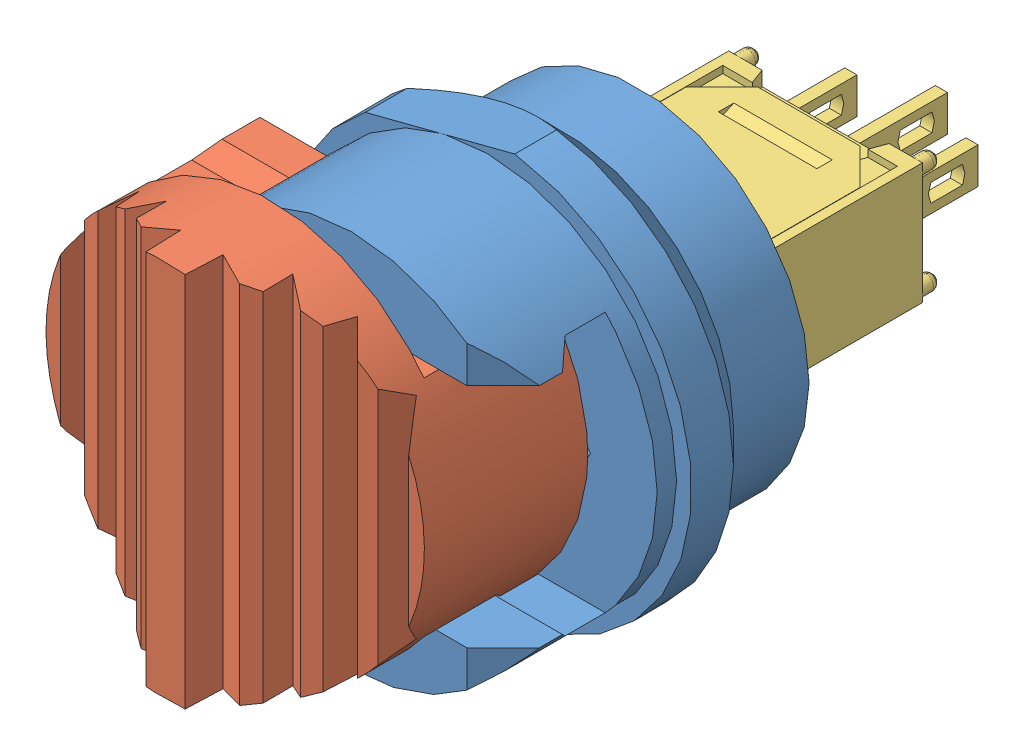
SolidWorks assembly SPD BRK Switch, configuration Default. Lengths in mm.
Overall size (19.33 17.7 29.74).
4 component instances, 4 part files, 9 mates.
Components (placement in the parent):
- SPD BRK Switch Body-1: SPD BRK Switch Body [Default] at origin size (17.14 17.7 12.04)
- SPD BRK Switch Cap-1: SPD BRK Switch Cap [Default] at (-2.8116 0 0.1016) size (15.88 15.88 9.81)
- 200MSPxT1B1M1QE-1: 200MSPxT1B1M1QE [200MSP5T1B1M1QEH] at (0 0 -12.6025) size (8.13 6 27)
- HDW211048UNSHEXNUT-1: HDW211048UNSHEXNUT [Default] at (0 0 -0.2675) x (-0.866025 -0.5 0) z (0.5 -0.866025 0) size (7 1.32 8.08)
Mates (geometry in assembly coordinates):
- Concentric1: concentric aligned: cylinder of SPD BRK Switch Body-1 through (0 0 -9.3345) axis (0 0 1) radius 7.1501; cylinder of 200MSPxT1B1M1QE-1 through (0 0 -5.022) axis (0 0 1) radius 2.3
- Coincident1: coincident anti-aligned: plane of SPD BRK Switch Body-1 through (-4.0005 0 -4.7625) normal (0 0 -1); plane of 200MSPxT1B1M1QE-1 through (3.3 -3.3 -4.7625) normal (0 0 1)
- Perpendicular1: perpendicular: plane of SPD BRK Switch Cap-1 through (-3.6371 0 12.2809) normal (-0.999133 0 0.041631); plane of 200MSPxT1B1M1QE-1 through (-4.065 2.54 -12.6025) normal (0 1 0)
- Width1: width anti-aligned: plane of SPD BRK Switch Cap-1 through (-2.8116 4.699 7.8359) normal (0 1 0); plane of SPD BRK Switch Cap-1 through (-2.8116 -4.699 4.0259) normal (0 -1 0); plane of SPD BRK Switch Body-1 through (0 4.7625 4.0259) normal (0 -1 0); plane of SPD BRK Switch Body-1 through (0 -4.7625 7.2771) normal (0 1 0)
- Coincident2: coincident: plane of SPD BRK Switch Body-1 through (0 5.461 4.0259) normal (0 0 -1); plane of SPD BRK Switch Cap-1 through (-2.8116 4.699 4.0259) normal (0 0 1)
- Coincident3: coincident: line of SPD BRK Switch Cap-1 through (-2.8116 0 -7.2771) axis (0 0 1); point of 200MSPxT1B1M1QE-1
- Concentric2: concentric anti-aligned: cylinder of 200MSPxT1B1M1QE-1 through (0 0 -5.022) axis (0 0 1) radius 2.3; cylinder of HDW211048UNSHEXNUT-1 through (0 0 -0.2675) axis (0 0 -1) radius 2.413
- Parallel1: parallel anti-aligned: plane of SPD BRK Switch Body-1 through (-2.1264 -3.683 -14.4268) normal (0 1 0); plane of HDW211048UNSHEXNUT-1 through (2.0207 -3.5 -1.5875) normal (0 -1 0)
- Coincident4: coincident anti-aligned: plane of SPD BRK Switch Body-1 through (8.5725 0 -1.5875) normal (0 0 1); plane of HDW211048UNSHEXNUT-1 through (0 0 -1.5875) normal (0 0 -1)
